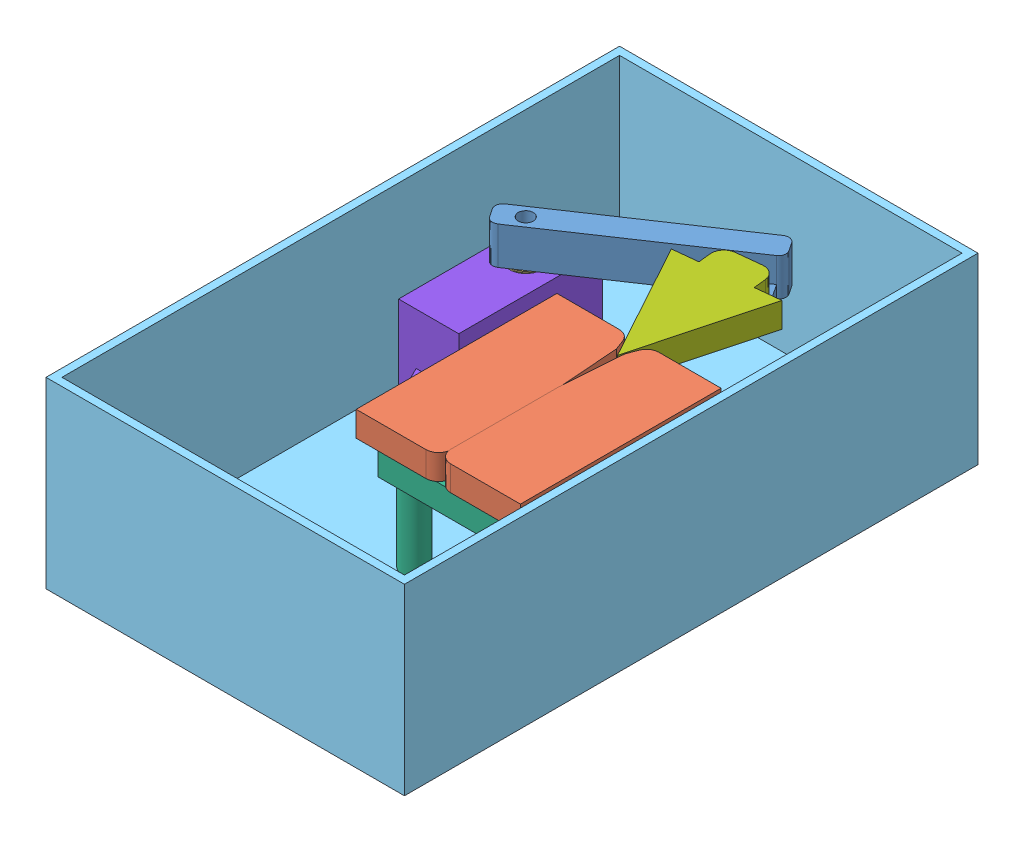
SolidWorks assembly Assembly, configuration Default. Lengths in mm.
Overall size (142.88 73.02 228.6).
9 component instances, 8 part files, 15 mates.
Components (placement in the parent):
- axe-1: axe [Default] at (146.8271 150.3623 -4.0745) x (0.830092 0 -0.557626) z (0.557626 0 0.830092) size (86 15 22.33)
- block-2: block [Default] at (202.1882 165.3623 58.0277) x (-1 0 0) z (0 0 1) size (65.45 20 80)
- hs-422-1: hs-422 [Default] at (136.8043 146.2221 20.4857) x (0 0 1) z (-1 0 0) size (52.83 40.97 19.69)
  - servo body-1: servo body [Default] x (1 0 0) z (0 0 -1) size (52.83 37.52 19.69)
  - servo output-1: servo output [Default] at (-10.3124 3.6322 0) x (0.949995 0 0.312266) z (-0.312266 0 0.949995) size (5.8 3.96 5.8)
- Basic-ForSizing-1: Basic-ForSizing [Default] at (170.6586 112.8465 27.5103) size (142.88 73.02 228.6)
- block_holder-1: block_holder [Default] at (193.0266 145.3623 121.8113) size (50 42.52 16.58)
- axe_head-1: axe_head [Default] at (199.0792 155.3623 3.9841) x (0.994293 0 -0.106685) z (0.106685 0 0.994293) size (40 15 60)
- servo_holder_hs422-1: servo_holder_hs422 [Default] at (136.8043 112.8465 20.2733) x (-1 0 0) z (0 0 -1) size (24 37.5 71.2)
Mates (geometry in assembly coordinates):
- Coincident2: coincident aligned: plane of axe-1 through (198.4894 165.3623 -28.9133) normal (0 1 0); plane of block-2 through (210.0958 165.3623 35.4102) normal (0 1 0)
- Coincident3: coincident anti-aligned: plane of axe-1 through (198.4894 150.3623 -28.9133) normal (0 -1 0); plane of hs-422-1/servo body-1 through (136.8043 150.3623 10.1733) normal (0 1 0)
- Parallel2: parallel anti-aligned: plane of hs-422-1/servo body-1 through (126.9618 146.2221 0.1657) normal (0 0 -1); plane of assembly through (0 0 0) normal (0 0 1)
- Coincident6: coincident anti-aligned: plane of hs-422-1/servo body-1 through (136.8043 112.8465 20.4857) normal (0 -1 0); plane of Basic-ForSizing-1 through (170.6586 112.8465 27.5103) normal (0 1 0)
- Concentric3: concentric anti-aligned: circle of axe-1; circle of hs-422-1/servo body-1
- Coincident7: coincident anti-aligned: plane of block-2 through (194.2806 155.3623 35.4102) normal (0 -1 0); plane of block_holder-1 through (193.0266 155.3623 121.8113) normal (0 1 0)
- Parallel4: parallel anti-aligned: plane of block_holder-1 through (177.0882 155.3623 92.8272) normal (0 0 -1); plane of assembly through (0 0 0) normal (0 0 1)
- Parallel5: parallel anti-aligned: line of block-2 through (234.9124 155.3623 110.4102) axis (-1 0 0); line of block_holder-1 through (177.0882 145.3623 109.4102) axis (1 0 0)
- Coincident10: coincident: line of block-2 through (202.0882 155.3623 105.4102) axis (0 0 -1); moEndPointRef_w of block_holder-1
- Distance1: distance = 1 mm aligned: plane of block_holder-1 through (177.0882 155.3623 109.4102) normal (0 0 1); plane of block-2 through (207.0882 155.3623 110.4102) normal (0 0 1)
- Coincident11: coincident anti-aligned: plane of axe-1 through (202.877 155.3623 -17.0018) normal (0 1 0); plane of axe_head-1 through (201.2454 155.3623 -15.3765) normal (0 -1 0)
- Concentric4: concentric anti-aligned: circle of axe-1; circle of axe_head-1
- Coincident13: coincident anti-aligned: plane of Basic-ForSizing-1 through (170.6586 112.8465 27.5103) normal (0 1 0); plane of servo_holder_hs422-1 through (136.8043 112.8465 20.2733) normal (0 -1 0)
- Parallel6: parallel anti-aligned: plane of hs-422-1/servo body-1 through (146.6468 146.2221 0.1657) normal (1 0 0); plane of servo_holder_hs422-1 through (146.8043 148.8465 46.8733) normal (-1 0 0)
- Concentric6: concentric aligned: circle of hs-422-1/servo body-1; circle of servo_holder_hs422-1
